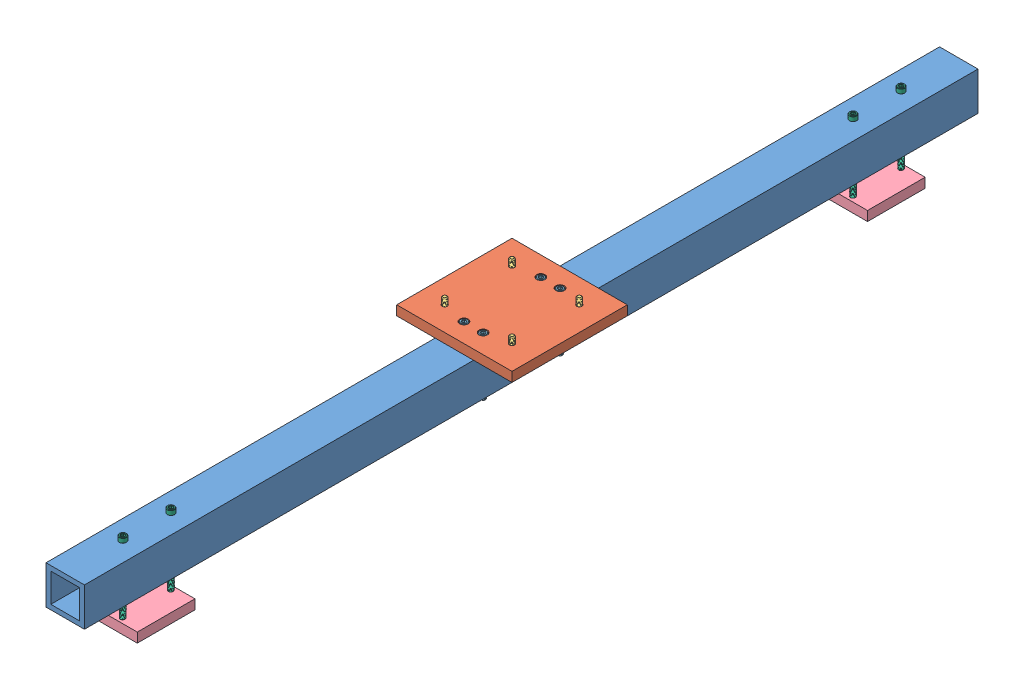
SolidWorks assembly roofMount, configuration Default. Lengths in mm.
Overall size (152.4 125.49 1181.1).
20 component instances, 7 part files, 41 mates.
Components (placement in the parent):
- cross_beam_ctw-1: cross_beam_ctw [Default] at (558.6291 655.2124 258.7207) size (50.8 50.8 1181.1)
- mounting_plate-1: mounting_plate [Default] at (558.6291 680.6124 849.2707) size (152.4 12.7 152.4)
- short1.4-20-1: short1.4-20 [91221A960] at (514.1791 702.8374 893.7207) x (1 0 0) z (0 1 0) size (9.53 9.53 23.61)
- short1.4-20-4: short1.4-20 [91221A960] at (514.1791 702.8374 804.8207) x (1 0 0) z (0 1 0) size (9.53 9.53 23.61)
- short1.4-20-7: short1.4-20 [91221A960] at (603.0791 702.8374 804.8207) x (1 0 0) z (0 1 0) size (9.53 9.53 23.61)
- short1.4-20-8: short1.4-20 [91221A960] at (603.0791 702.8374 893.7207) x (1 0 0) z (0 1 0) size (9.53 9.53 23.61)
- clamp_bottom-1: clamp_bottom [Default] at (558.6291 579.0124 366.6707) x (0 0 -1) z (1 0 0) size (76.2 12.7 50.8)
- clamp_bottom-2: clamp_bottom [Default] at (558.6291 579.0124 1331.8707) x (0 0 -1) z (1 0 0) size (76.2 12.7 50.8)
- long1.4-20-5: long1.4-20 [90044A128] at (545.9291 652.0374 798.4707) x (0 -1 0) z (-0.184003 0 0.982926) size (77.03 9.53 9.53)
- long1.4-20-6: long1.4-20 [90044A128] at (571.3291 652.0374 798.4707) x (0 -1 0) z (0 0 1) size (77.03 9.53 9.53)
- long1.4-20-7: long1.4-20 [90044A128] at (545.9291 652.0374 900.0707) x (0 -1 0) z (0 0 1) size (77.03 9.53 9.53)
- long1.4-20-8: long1.4-20 [90044A128] at (571.3291 652.0374 900.0707) x (0 -1 0) z (0 0 1) size (77.03 9.53 9.53)
- 1.4-20_len4.0-1: 1.4-20_len4.0 [90044A131] at (558.6291 629.8124 398.4207) x (0 -1 0) z (0 0 1) size (108.78 9.53 9.53)
- 1.4-20_len4.0-2: 1.4-20_len4.0 [90044A131] at (558.6291 629.8124 1363.6207) x (0 -1 0) z (0 0 1) size (108.78 9.53 9.53)
- 1.4-20_len4.0-3: 1.4-20_len4.0 [90044A131] at (558.6291 629.8124 334.9207) x (0 -1 0) z (0 0 1) size (108.78 9.53 9.53)
- 1.4-20_len4.0-4: 1.4-20_len4.0 [90044A131] at (558.6291 629.8124 1300.1207) x (0 -1 0) z (0 0 1) size (108.78 9.53 9.53)
- 1.4-20_nut-1: 1.4-20_nut [97135A210] at (545.9291 629.8124 900.0707) x (-0.837169 0 -0.546944) z (-0.546944 0 0.837169) size (11.11 8.13 12.83)
- 1.4-20_nut-2: 1.4-20_nut [97135A210] at (545.9291 629.8124 798.4707) x (-0.837169 0 -0.546944) z (-0.546944 0 0.837169) size (11.11 8.13 12.83)
- 1.4-20_nut-3: 1.4-20_nut [97135A210] at (571.3291 629.8124 798.4707) x (-0.837169 0 -0.546944) z (-0.546944 0 0.837169) size (11.11 8.13 12.83)
- 1.4-20_nut-4: 1.4-20_nut [97135A210] at (571.3291 629.8124 900.0707) x (-0.837169 0 -0.546944) z (-0.546944 0 0.837169) size (11.11 8.13 12.83)
Mates (geometry in assembly coordinates):
- Coincident5: coincident anti-aligned: plane of cross_beam_ctw-1 through (584.0291 680.6124 1439.8207) normal (0 1 0); plane of mounting_plate-1 through (558.6291 680.6124 849.2707) normal (0 -1 0)
- Coincident6: coincident anti-aligned: plane of mounting_plate-1 through (606.4573 686.9624 804.8207) normal (0 -1 0); plane of short1.4-20-7 through (603.0791 686.9624 804.8207) normal (0 1 0)
- Concentric7: concentric anti-aligned: cylinder of mounting_plate-1 through (603.0791 680.6124 804.8207) axis (0 -1 0) radius 5.5563; cylinder of short1.4-20-7 through (603.0791 680.6124 804.8207) axis (0 1 0) radius 4.7625
- Coincident7: coincident anti-aligned: plane of mounting_plate-1 through (517.5573 686.9624 804.8207) normal (0 -1 0); plane of short1.4-20-4 through (514.1791 686.9624 804.8207) normal (0 1 0)
- Concentric8: concentric anti-aligned: cylinder of mounting_plate-1 through (514.1791 680.6124 804.8207) axis (0 -1 0) radius 5.5563; cylinder of short1.4-20-4 through (514.1791 680.6124 804.8207) axis (0 1 0) radius 4.7625
- Coincident8: coincident anti-aligned: plane of mounting_plate-1 through (517.5573 686.9624 893.7207) normal (0 -1 0); plane of short1.4-20-1 through (514.1791 686.9624 893.7207) normal (0 1 0)
- Concentric9: concentric anti-aligned: cylinder of mounting_plate-1 through (514.1791 680.6124 893.7207) axis (0 -1 0) radius 5.5563; cylinder of short1.4-20-1 through (514.1791 680.6124 893.7207) axis (0 1 0) radius 4.7625
- Coincident9: coincident anti-aligned: plane of mounting_plate-1 through (606.4573 686.9624 893.7207) normal (0 -1 0); plane of short1.4-20-8 through (603.0791 686.9624 893.7207) normal (0 1 0)
- Concentric10: concentric anti-aligned: cylinder of mounting_plate-1 through (603.0791 680.6124 893.7207) axis (0 -1 0) radius 5.5563; cylinder of short1.4-20-8 through (603.0791 680.6124 893.7207) axis (0 1 0) radius 4.7625
- Concentric19: concentric anti-aligned: cylinder of mounting_plate-1 through (545.9291 693.3124 798.4707) axis (0 1 0) radius 5.5563; cylinder of long1.4-20-5 through (545.9291 686.9624 798.4707) axis (0 -1 0) radius 4.7625
- Coincident16: coincident anti-aligned: circle of mounting_plate-1; plane of long1.4-20-5 through (550.2982 686.9624 799.2886) normal (0 -1 0)
- Concentric20: concentric anti-aligned: cylinder of cross_beam_ctw-1 through (545.9291 680.6124 798.4707) axis (0 1 0) radius 3.175; circle of long1.4-20-5
- Coincident17: coincident anti-aligned: plane of mounting_plate-1 through (574.7073 686.9624 798.4707) normal (0 1 0); plane of long1.4-20-6 through (575.7741 686.9624 798.4707) normal (0 -1 0)
- Concentric21: concentric anti-aligned: cylinder of mounting_plate-1 through (571.3291 693.3124 798.4707) axis (0 1 0) radius 5.5563; cylinder of long1.4-20-6 through (571.3291 686.9624 798.4707) axis (0 -1 0) radius 4.7625
- Concentric22: concentric anti-aligned: cylinder of cross_beam_ctw-1 through (571.3291 680.6124 798.4707) axis (0 1 0) radius 3.175; circle of long1.4-20-6
- Coincident18: coincident anti-aligned: plane of mounting_plate-1 through (549.3073 686.9624 900.0707) normal (0 1 0); plane of long1.4-20-7 through (550.3741 686.9624 900.0707) normal (0 -1 0)
- Concentric23: concentric anti-aligned: cylinder of mounting_plate-1 through (545.9291 693.3124 900.0707) axis (0 1 0) radius 5.5563; circle of long1.4-20-7
- Coincident19: coincident anti-aligned: plane of mounting_plate-1 through (574.7073 686.9624 900.0707) normal (0 1 0); plane of long1.4-20-8 through (575.7741 686.9624 900.0707) normal (0 -1 0)
- Concentric24: concentric anti-aligned: cylinder of mounting_plate-1 through (571.3291 693.3124 900.0707) axis (0 1 0) radius 5.5563; cylinder of long1.4-20-8 through (571.3291 686.9624 900.0707) axis (0 -1 0) radius 4.7625
- Coincident20: coincident anti-aligned: plane of cross_beam_ctw-1 through (584.0291 680.6124 1439.8207) normal (0 1 0); plane of 1.4-20_len4.0-4 through (563.0741 680.6124 1300.1207) normal (0 -1 0)
- Concentric25: concentric anti-aligned: cylinder of cross_beam_ctw-1 through (558.6291 680.6124 1300.1207) axis (0 1 0) radius 3.175; cylinder of 1.4-20_len4.0-4 through (558.6291 680.6124 1300.1207) axis (0 -1 0) radius 4.7625
- Coincident21: coincident aligned: plane of clamp_bottom-2 through (558.6291 579.0124 1331.8707) normal (0 -1 0); plane of 1.4-20_len4.0-4 through (558.6291 579.0124 1300.1207) normal (0 -1 0)
- Coincident22: coincident anti-aligned: plane of cross_beam_ctw-1 through (584.0291 680.6124 1439.8207) normal (0 1 0); plane of 1.4-20_len4.0-2 through (563.0741 680.6124 1363.6207) normal (0 -1 0)
- Concentric26: concentric anti-aligned: cylinder of cross_beam_ctw-1 through (558.6291 680.6124 1363.6207) axis (0 1 0) radius 3.175; cylinder of 1.4-20_len4.0-2 through (558.6291 680.6124 1363.6207) axis (0 -1 0) radius 4.7625
- Coincident23: coincident anti-aligned: plane of cross_beam_ctw-1 through (584.0291 680.6124 1439.8207) normal (0 1 0); plane of 1.4-20_len4.0-1 through (563.0741 680.6124 398.4207) normal (0 -1 0)
- Coincident24: coincident anti-aligned: plane of cross_beam_ctw-1 through (584.0291 680.6124 1439.8207) normal (0 1 0); plane of 1.4-20_len4.0-3 through (563.0741 680.6124 334.9207) normal (0 -1 0)
- Concentric27: concentric anti-aligned: cylinder of cross_beam_ctw-1 through (558.6291 680.6124 334.9207) axis (0 1 0) radius 3.175; cylinder of 1.4-20_len4.0-3 through (558.6291 680.6124 334.9207) axis (0 -1 0) radius 4.7625
- Concentric28: concentric anti-aligned: cylinder of cross_beam_ctw-1 through (558.6291 680.6124 398.4207) axis (0 1 0) radius 3.175; cylinder of 1.4-20_len4.0-1 through (558.6291 680.6124 398.4207) axis (0 -1 0) radius 4.7625
- Coincident25: coincident aligned: plane of clamp_bottom-1 through (558.6291 579.0124 366.6707) normal (0 -1 0); plane of 1.4-20_len4.0-3 through (558.6291 579.0124 334.9207) normal (0 -1 0)
- Concentric29: concentric anti-aligned: circle of clamp_bottom-1; circle of 1.4-20_len4.0-3
- Concentric30: concentric anti-aligned: circle of clamp_bottom-1; circle of 1.4-20_len4.0-1
- Concentric31: concentric anti-aligned: circle of clamp_bottom-2; circle of 1.4-20_len4.0-2
- Concentric32: concentric anti-aligned: circle of clamp_bottom-2; circle of 1.4-20_len4.0-4
- Coincident26: coincident anti-aligned: plane of cross_beam_ctw-1 through (584.0291 629.8124 1439.8207) normal (0 -1 0); plane of 1.4-20_nut-1 through (543.0321 629.8124 894.3461) normal (0 1 0)
- Concentric33: concentric anti-aligned: circle of long1.4-20-7; cylinder of 1.4-20_nut-1 through (545.9291 623.1216 900.0707) axis (0 1 0) radius 2.6099
- Coincident27: coincident anti-aligned: plane of cross_beam_ctw-1 through (584.0291 629.8124 1439.8207) normal (0 -1 0); plane of 1.4-20_nut-4 through (568.4321 629.8124 894.3461) normal (0 1 0)
- Concentric34: concentric anti-aligned: circle of long1.4-20-8; circle of 1.4-20_nut-4
- Coincident28: coincident anti-aligned: plane of cross_beam_ctw-1 through (584.0291 629.8124 1439.8207) normal (0 -1 0); plane of 1.4-20_nut-3 through (568.4321 629.8124 792.7461) normal (0 1 0)
- Coincident29: coincident anti-aligned: plane of cross_beam_ctw-1 through (584.0291 629.8124 1439.8207) normal (0 -1 0); plane of 1.4-20_nut-2 through (543.0321 629.8124 792.7461) normal (0 1 0)
- Concentric35: concentric anti-aligned: circle of long1.4-20-6; circle of 1.4-20_nut-3
- Concentric36: concentric anti-aligned: circle of long1.4-20-5; circle of 1.4-20_nut-2
